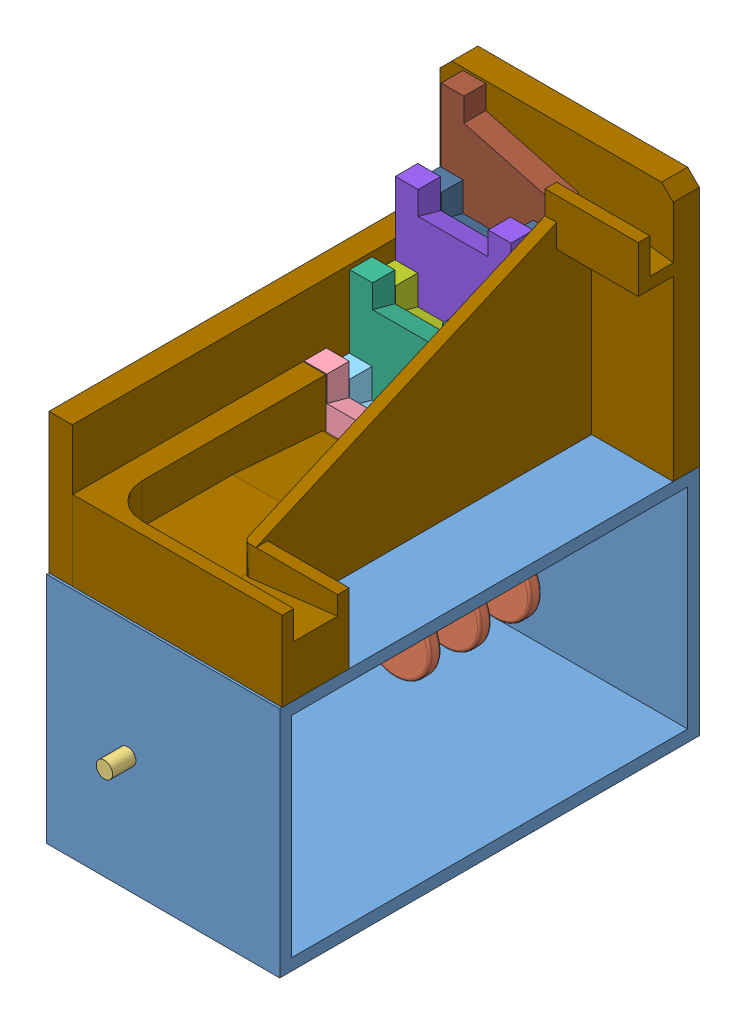
SolidWorks assembly 装配体2, configuration 默认. Lengths in mm.
Overall size (100 208.73 190.2).
11 component instances, 11 part files, 29 mates.
Components (placement in the parent):
- part-2: part [默认] at (-0.869 -50.4679 180) size (100 100 180)
- 凸輪-2: 凸輪 [默认] at (-15.869 -0.4679 180) x (-0.923728 -0.383049 0) z (0 0 -1) size (30 50 180)
- part9-2: part9 [默认] at (-15.869 -0.4679 270.2) size (7 7 10)
- 板塊1-1: 板塊1 [默认] at (-40.669 83.7694 160.2) size (49.6 60 9.6)
- 板塊2-1: 板塊2 [默认] at (-40.669 76.9748 150.4) size (49.6 71.68 9.6)
- 板塊3-1: 板塊3 [默认] at (-40.669 107.8794 140.6) size (49.6 84.11 9.6)
- 板塊4-1: 板塊4 [默认] at (-40.669 101.8348 130.8) size (49.6 96.54 9.6)
- 板塊5-1: 板塊5 [默认] at (-40.669 132.7394 121) size (49.6 108.97 9.6)
- 擋板-1: 擋板 [默认] at (-50.869 49.5321 90) size (100 108.73 179)
- 板塊6-2: 板塊6 [默认] at (-40.669 126.6948 111.3) size (49.6 121.4 9.4)
- 板塊7-2: 板塊7 [默认] at (-40.669 157.5994 101.6) size (49.6 133.83 9.4)
Mates (geometry in assembly coordinates):
- 同心3: concentric: cylinder of part-2 through (-15.869 -0.4679 90) axis (0 0 1) radius 3.25; cylinder of 凸輪-2 through (-15.869 -0.4679 90) axis (0 0 1) radius 3.125
- 重合3: coincident: plane of part-2 through (-50.869 49.5321 90) normal (0 0 -1); plane of 凸輪-2 through (-15.869 -0.4679 90) normal (0 0 -1)
- 同心4: concentric: cylinder of 凸輪-2 through (-15.869 -0.4679 90) axis (0 0 1) radius 3.125; cylinder of part9-2 through (-15.869 -0.4679 280.2) axis (0 0 -1) radius 3.5
- 距离1: distance = 0.2 mm: plane of part9-2 through (-15.869 -0.4679 270.2) normal (0 0 -1); plane of part-2 through (-50.869 49.5321 270) normal (0 0 1)
- 距离2: distance = 0.2 mm: plane of part-2 through (-40.869 -40.4679 170) normal (0 0 -1); plane of 板塊1-1 through (-40.669 83.7694 169.8) normal (0 0 1)
- 距离3: distance = 0 mm: plane of 板塊1-1 through (-40.669 23.7694 169.8) normal (0 -1 0); cylinder of 凸輪-2 through (-19.6995 8.7694 168.7) axis (0 0 -1) radius 15
- 距离4: distance = 0.2 mm: plane of 板塊1-1 through (8.931 83.7694 169.8) normal (1 0 0); line of part-2 through (9.131 49.5321 170) axis (0 0 -1)
- 距离5: distance = 0.2 mm: plane of 板塊2-1 through (-40.669 76.9748 160) normal (0 0 1); plane of 板塊1-1 through (-40.669 83.7694 160.2) normal (0 0 -1)
- 距离6: distance = 0.2 mm: plane of 板塊2-1 through (8.931 76.9748 160) normal (1 0 0); plane of part-2 through (9.131 -40.4679 101.4) normal (-1 0 0)
- 相切5: tangent: cylinder of 凸輪-2 through (-25.784 0.8334 159.5) axis (0 0 -1) radius 15; plane of 板塊2-1 through (-40.669 15.8334 160) normal (0 -1 0)
- 距离7: distance = 0.2 mm: plane of 板塊3-1 through (-40.669 107.8794 150.2) normal (0 0 1); plane of 板塊2-1 through (-40.669 76.9748 150.4) normal (0 0 -1)
- 距离8: distance = 0.2 mm: plane of 板塊3-1 through (8.931 107.8794 150.2) normal (1 0 0); plane of part-2 through (9.131 -40.4679 101.4) normal (-1 0 0)
- 相切6: tangent: cylinder of 凸輪-2 through (-5.954 -1.7693 148.2) axis (0 0 -1) radius 15; plane of 板塊3-1 through (-40.669 13.2307 150.2) normal (0 -1 0)
- 距离9: distance = 0.2 mm: plane of 板塊4-1 through (-40.669 101.8348 140.4) normal (0 0 1); plane of 板塊3-1 through (-40.669 107.8794 140.6) normal (0 0 -1)
- 距离10: distance = 0.2 mm: plane of 板塊4-1 through (-40.669 101.8348 140.4) normal (-1 0 0); plane of part-2 through (-40.869 -40.4679 101.4) normal (1 0 0)
- 相切7: tangent: cylinder of 凸輪-2 through (-25.784 0.8334 138) axis (0 0 -1) radius 15; plane of 板塊4-1 through (-40.669 15.8334 140.4) normal (0 -1 0)
- 距离11: distance = 0.2 mm: plane of 板塊5-1 through (-40.669 132.7394 130.6) normal (0 0 1); plane of 板塊4-1 through (-40.669 101.8348 130.8) normal (0 0 -1)
- 距离12: distance = 0.2 mm: plane of 板塊5-1 through (-40.669 132.7394 130.6) normal (-1 0 0); plane of part-2 through (-40.869 -40.4679 101.4) normal (1 0 0)
- 相切8: tangent: cylinder of 凸輪-2 through (-5.954 -1.7693 127.7) axis (0 0 -1) radius 15; plane of 板塊5-1 through (-40.669 13.2307 130.6) normal (0 -1 0)
- 重合19: coincident: plane of part-2 through (-0.869 49.5321 180) normal (0 1 0); plane of 擋板-1 through (-30.869 49.5321 170.2) normal (0 -1 0)
- 距离15: distance = 0.2 mm: plane of 擋板-1 through (-30.869 49.5321 170.2) normal (0 0 -1); plane of 板塊1-1 through (-40.669 73.2307 169.8) normal (0 0 1)
- 重合21: coincident: plane of 擋板-1 through (-50.869 49.5321 101.2) normal (-1 0 0); plane of part-2 through (-50.869 49.5321 90) normal (-1 0 0)
- 重合24: coincident: plane of part-2 through (-50.869 49.5321 90) normal (0 0 -1); plane of 擋板-1 through (-50.869 49.5321 90) normal (0 0 -1)
- 距离17: distance = 0.3 mm: plane of 板塊6-2 through (-40.669 126.6948 120.7) normal (0 0 1); plane of 板塊5-1 through (-40.669 132.7394 121) normal (0 0 -1)
- 距离18: distance = 0.2 mm: plane of 板塊6-2 through (8.931 126.6948 120.7) normal (1 0 0); plane of part-2 through (9.131 -40.4679 101.4) normal (-1 0 0)
- 相切11: tangent: cylinder of 凸輪-2 through (-25.784 0.8334 116.5) axis (0 0 -1) radius 15; plane of 板塊6-2 through (-40.669 15.8334 120.7) normal (0 -1 0)
- 距离19: distance = 0.3 mm: plane of 板塊7-2 through (-40.669 157.5994 111) normal (0 0 1); plane of 板塊6-2 through (-40.669 126.6948 111.3) normal (0 0 -1)
- 距离20: distance = 0.2 mm: plane of 板塊7-2 through (8.931 157.5994 111) normal (1 0 0); plane of part-2 through (9.131 -40.4679 101.4) normal (-1 0 0)
- 相切12: tangent: cylinder of 凸輪-2 through (-5.954 -1.7693 107.2) axis (0 0 -1) radius 15; plane of 板塊7-2 through (-40.669 13.2307 111) normal (0 -1 0)
